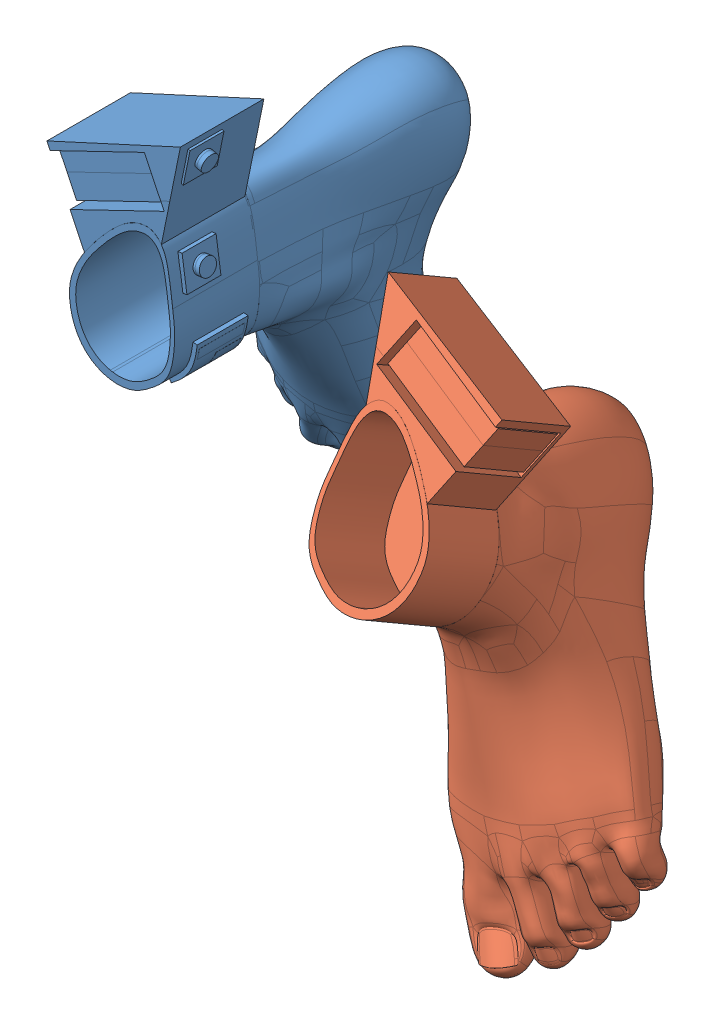
SolidWorks assembly Feet_heelstep, configuration Default. Lengths in mm.
Overall size (570.75 841.21 612.59).
3 component instances, 3 part files, 0 mates.
Components (placement in the parent):
- foot1-1: foot1 [Right] at (256.4291 194.2322 323.4055) size (245.52 568.46 358.41)
- Mirrorfoot1-2: Mirrorfoot1 [Right] at (383.5709 194.2322 323.4055) x (-1 0 0) z (0 0 -1) (suppressed, hidden)
- Mirrorfoot1-4: Mirrorfoot1 [Right] at (225.6912 -100.4273 414.0648) x (-0.997569 -0.033176 0.061282) z (-0.035643 -0.512769 -0.857787) size (245.52 568.46 358.41)
